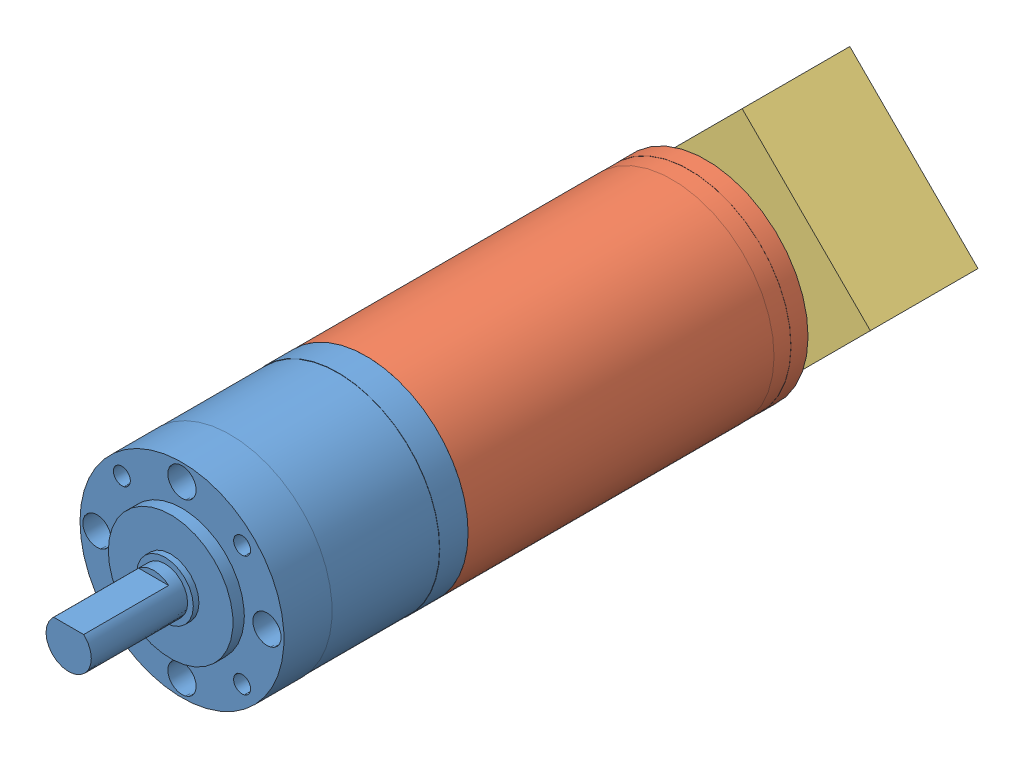
SolidWorks assembly Motor Set, configuration 預設. Lengths in mm.
Overall size (53.33 53.33 131.5).
3 component instances, 3 part files, 4 mates.
Components (placement in the parent):
- Gear Unit-1: Gear Unit [預設] at origin size (36 36 52.5)
- Motor-1: Motor [預設] at (0 0 -81) x (-0.883001 -0.46937 0) z (0 0 1) size (36 36 90)
- Encoder-2: Encoder [預設] at (0 0 -84) x (0.707107 -0.707107 0) z (0 0 -1) size (32 41 19)
Mates (geometry in assembly coordinates):
- 重合/共線/共點1: coincident: circle of Gear Unit-1; circle of Motor-1
- 重合/共線/共點3: coordinate: point of Gear Unit-1; point of assembly
- 重合/共線/共點8: coincident: circle of Motor-1; circle of Encoder-2
- 角度1: planar angle = 0.785398 rad: plane of Encoder-2 through (6.364 28.9914 -103) normal (0.707107 0.707107 0); plane of assembly through (0 0 0) normal (1 0 0)
